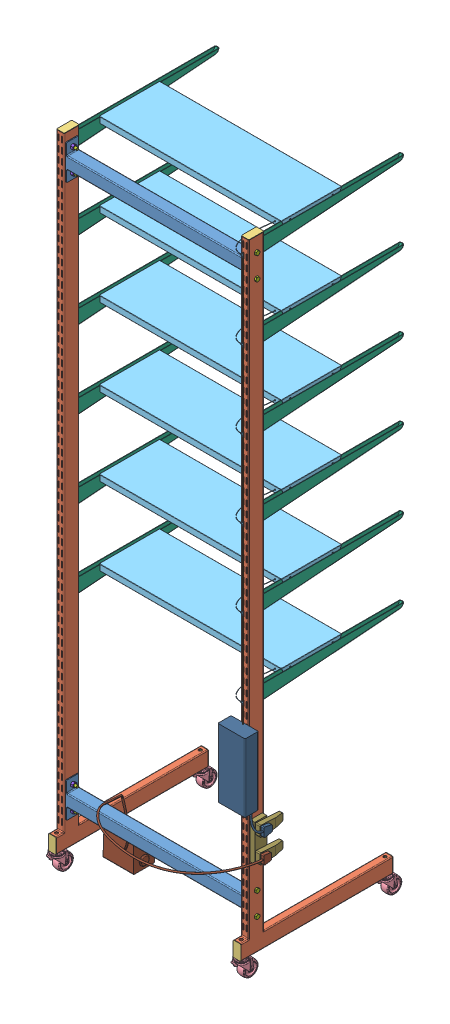
SolidWorks assembly elec system, configuration Default. Lengths in mm.
Overall size (697.81 2115 564.83).
53 component instances, 13 part files, 139 mates.
Components (placement in the parent):
- TB-600-1: TB-600 [Default] at (0 2029.5 0) size (585 115 40)
- TB-600-2: TB-600 [Default] at (0 205.5 0) size (585 115 40)
- TSU-F-L-P-1: TSU-F-L-P [Default] at (305 113.5 -25) size (25 2050 500)
- TSU-F-L-P-2: TSU-F-L-P [Default] at (-305 113.5 -25) size (25 2050 500)
- TSU-CAP-1: TSU-CAP [Default] at (-305.1 113.6 -39.9) x (-1 0 0) z (0 0 -1) size (25.2 50.2 6.5)
- TSU-CAP-2: TSU-CAP [Default] at (304.9 113.6 -39.9) x (-1 0 0) z (0 0 -1) size (25.2 50.2 6.5)
- TSU-CAP-3: TSU-CAP [Default] at (305.1 1703.4 -25.1) x (1 0 0) z (0 1 0) size (25.2 50.2 6.5)
- TSU-CAP-4: TSU-CAP [Default] at (304.9 113.6 -360.1) size (25.2 50.2 6.5)
- TSU-CAP-5: TSU-CAP [Default] at (-304.9 1703.4 -25.1) x (1 0 0) z (0 1 0) size (25.2 50.2 6.5)
- TSU-CAP-6: TSU-CAP [Default] at (-304.9 113.6 -360.1) size (25.2 50.2 6.5)
- 2834T320_THREADED-STEM SWIVEL CASTER-1: 2834T320_THREADED-STEM SWIVEL CASTER [2834T32] at (305 82.55 -437.5) x (0 0 -1) z (1 0 0) size (67.73 101.87 56.07)
- 2834T320_THREADED-STEM SWIVEL CASTER-2: 2834T320_THREADED-STEM SWIVEL CASTER [2834T32] at (-305 82.55 37.5) x (0 0 -1) z (1 0 0) size (67.73 101.87 56.07)
- 2834T320_THREADED-STEM SWIVEL CASTER-3: 2834T320_THREADED-STEM SWIVEL CASTER [2834T32] at (305 82.55 37.5) x (0 0 -1) z (1 0 0) size (67.73 101.87 56.07)
- 2834T320_THREADED-STEM SWIVEL CASTER-4: 2834T320_THREADED-STEM SWIVEL CASTER [2834T32] at (-305 82.55 -437.5) x (0 0 -1) z (1 0 0) size (67.73 101.87 56.07)
- TSS-600-1: TSS-600 [Default] at (0 818 -198.7822) size (607 37.13 331.17)
- TSUB-1: TSUB [Default] at (305 766.5 -25) x (-1 0 0) z (0 0 -1) size (14.07 50.86 484.03)
- TSUB-2: TSUB [Default] at (-305 766.5 -25) x (-1 0 0) z (0 0 -1) size (14.07 50.86 484.03)
- TSUB-3: TSUB [Default] at (-305 1022.5 -25) x (-1 0 0) z (0 0 -1) size (14.07 50.86 484.03)
- TSUB-4: TSUB [Default] at (305 1022.5 -25) x (-1 0 0) z (0 0 -1) size (14.07 50.86 484.03)
- TSS-600-2: TSS-600 [Default] at (0 1074 -198.7822) size (607 37.13 331.17)
- TSUB-5: TSUB [Default] at (-305 1534.5 -25) x (-1 0 0) z (0 0 -1) size (14.07 50.86 484.03)
- TSUB-6: TSUB [Default] at (305 1534.5 -25) x (-1 0 0) z (0 0 -1) size (14.07 50.86 484.03)
- TSS-600-3: TSS-600 [Default] at (0 1586 -198.7822) size (607 37.13 331.17)
- TSUB-7: TSUB [Default] at (-305 2046.5 -25) x (-1 0 0) z (0 0 -1) size (14.07 50.86 484.03)
- TSUB-8: TSUB [Default] at (305 2046.5 -25) x (-1 0 0) z (0 0 -1) size (14.07 50.86 484.03)
- TSS-600-4: TSS-600 [Default] at (0 2098 -198.7822) size (607 37.13 331.17)
- TSUB-9: TSUB [Default] at (-305 1278.5 -25) x (-1 0 0) z (0 0 -1) size (14.07 50.86 484.03)
- TSUB-10: TSUB [Default] at (305 1278.5 -25) x (-1 0 0) z (0 0 -1) size (14.07 50.86 484.03)
- TSS-600-5: TSS-600 [Default] at (0 1330 -198.7822) size (607 37.13 331.17)
- TSUB-11: TSUB [Default] at (-305 1790.5 -25) x (-1 0 0) z (0 0 -1) size (14.07 50.86 484.03)
- TSUB-12: TSUB [Default] at (305 1790.5 -25) x (-1 0 0) z (0 0 -1) size (14.07 50.86 484.03)
- TSS-600-6: TSS-600 [Default] at (0 1842 -198.7822) size (607 37.13 331.17)
- hex bolt gradeab2_bsi-10: hex bolt gradeab2_bsi [BS EN 28765 - M8x1 x 45 x 22-N] at (322.8 2067 0) x (-1 0 0) z (0 -0.924225 -0.381849) size (50.3 15.01 13)
- hex bolt gradeab2_bsi-11: hex bolt gradeab2_bsi [BS EN 28765 - M8x1 x 45 x 22-N] at (322.8 1992 0) x (-1 0 0) z (0 -0.999974 0.007224) size (50.3 15.01 13)
- hex bolt gradeab2_bsi-12: hex bolt gradeab2_bsi [BS EN 28765 - M8x1 x 45 x 22-N] at (-322.8 2067 0) size (50.3 15.01 13)
- hex bolt gradeab2_bsi-13: hex bolt gradeab2_bsi [BS EN 28765 - M8x1 x 45 x 22-N] at (-322.8 1992 0) size (50.3 15.01 13)
- hex bolt gradeab2_bsi-14: hex bolt gradeab2_bsi [BS EN 28765 - M8x1 x 45 x 22-N] at (-322.8 168 0) size (50.3 15.01 13)
- hex bolt gradeab2_bsi-15: hex bolt gradeab2_bsi [BS EN 28765 - M8x1 x 45 x 22-N] at (-322.8 243 0) size (50.3 15.01 13)
- hex bolt gradeab2_bsi-16: hex bolt gradeab2_bsi [BS EN 28765 - M8x1 x 45 x 22-N] at (322.8 168 0) x (-1 0 0) z (0 0.924225 0.381849) size (50.3 15.01 13)
- hex bolt gradeab2_bsi-17: hex bolt gradeab2_bsi [BS EN 28765 - M8x1 x 45 x 22-N] at (322.8 243 0) x (-1 0 0) z (0 -0.924225 -0.381849) size (50.3 15.01 13)
- hex nut gradec_bsi-1: hex nut gradec_bsi [BS EN 24034 - M8 - N] at (281.6 2067 0) x (0 0 1) z (-1 0 0) size (13 15.01 7.9)
- hex nut gradec_bsi-2: hex nut gradec_bsi [BS EN 24034 - M8 - N] at (281.6 1992 0) x (0 0 1) z (-1 0 0) size (13 15.01 7.9)
- hex nut gradec_bsi-3: hex nut gradec_bsi [BS EN 24034 - M8 - N] at (-281.6 2067 0) x (0 0 -1) z (1 0 0) size (13 15.01 7.9)
- hex nut gradec_bsi-4: hex nut gradec_bsi [BS EN 24034 - M8 - N] at (-281.6 1992 0) x (0 0.383049 0.923728) z (1 0 0) size (13 15.01 7.9)
- hex nut gradec_bsi-5: hex nut gradec_bsi [BS EN 24034 - M8 - N] at (-281.6 243 0) x (0 0 -1) z (1 0 0) size (13 15.01 7.9)
- hex nut gradec_bsi-6: hex nut gradec_bsi [BS EN 24034 - M8 - N] at (281.6 243 0) x (0 0 1) z (-1 0 0) size (13 15.01 7.9)
- hex nut gradec_bsi-7: hex nut gradec_bsi [BS EN 24034 - M8 - N] at (281.6 168 0) x (0 0 1) z (-1 0 0) size (13 15.01 7.9)
- hex nut gradec_bsi-8: hex nut gradec_bsi [BS EN 24034 - M8 - N] at (-281.6 168 0) x (0 0 -1) z (1 0 0) size (13 15.01 7.9)
- Part4-1: Part4 [Default] at origin
- Part1-1: Part1 [Default] at (0 2060.8692 -198.7822) x (-1 0 0) z (0 -1 0) size (2 2 1357)
- Part2-1: Part2 [Default] at (305 113.5 -25) x (0 0 -1) z (1 0 0) size (82.56 307.09 97.63)
- ele-1: ele [Default] at (0 5 -225) x (1 0 0) z (0 1 0) size (624.24 196.22 364.08)
- power brick-1: power brick [Default] at (317.5 113.5 -25) x (0 0 -1) z (1 0 0) size (82.62 120 30)
Mates (geometry in assembly coordinates):
- Coincident5: coincident aligned: plane of TB-600-2 through (0 205.5 0) normal (1 0 0)
- Coincident6: coincident aligned: plane of TB-600-2 through (0 205.5 0) normal (0 0 1)
- Tangent1: tangent anti-aligned: torus of 2834T320_THREADED-STEM SWIVEL CASTER-1
- Concentric5: concentric anti-aligned: cylinder of TSU-F-L-P-1 through (305 113.5 -437.5) axis (0 -1 0) radius 5.1; cylinder of 2834T320_THREADED-STEM SWIVEL CASTER-1 through (305 101.6 -437.5) axis (0 1 0) radius 4.7625
- Coincident7: coincident anti-aligned: plane of TB-600-2 through (292.5 205.5 0) normal (1 0 0); plane of TSU-F-L-P-1 through (292.5 2113.5 -22) normal (-1 0 0)
- Concentric6: concentric anti-aligned: cylinder of TB-600-2 through (292.5 243 0) axis (-1 0 0) radius 4.5; cylinder of TSU-F-L-P-1 through (290.9 243 0) axis (1 0 0) radius 4.5
- Coincident8: coincident anti-aligned: plane of TSU-F-L-P-1 through (305 63.5 -450) normal (0 -1 0); plane of 2834T320_THREADED-STEM SWIVEL CASTER-1 through (305 63.5 -421.3957) normal (0 1 0)
- Concentric7: concentric anti-aligned: cylinder of TB-600-1 through (292.5 2067 0) axis (-1 0 0) radius 4.5; cylinder of TSU-F-L-P-1 through (292.5 2067 0) axis (1 0 0) radius 4.5
- Coincident9: coincident anti-aligned: plane of TB-600-1 through (292.5 2029.5 0) normal (1 0 0); plane of TSU-F-L-P-1 through (292.5 2113.5 -22) normal (-1 0 0)
- Concentric8: concentric aligned: cylinder of TB-600-2 through (-292.5 168 0) axis (1 0 0) radius 4.5; cylinder of TSU-F-L-P-2 through (-319.1 168 0) axis (1 0 0) radius 4.5
- Coincident10: coincident anti-aligned: plane of TB-600-2 through (-292.5 205.5 0) normal (-1 0 0); plane of TSU-F-L-P-2 through (-292.5 2113.5 -22) normal (1 0 0)
- Concentric9: concentric anti-aligned: cylinder of TSU-F-L-P-2 through (-305 113.5 -437.5) axis (0 -1 0) radius 5.1; cylinder of 2834T320_THREADED-STEM SWIVEL CASTER-4 through (-305 101.6 -437.5) axis (0 1 0) radius 4.7625
- Concentric10: concentric aligned: cylinder of TB-600-1 through (-292.5 1992 0) axis (1 0 0) radius 4.5; cylinder of TSU-F-L-P-2 through (-317.5 1992 0) axis (1 0 0) radius 4.5
- Concentric11: concentric aligned: cylinder of TB-600-1 through (-292.5 2067 0) axis (1 0 0) radius 4.5; cylinder of TSU-F-L-P-2 through (-317.5 2067 0) axis (1 0 0) radius 4.5
- Parallel4: parallel aligned: plane of TSU-F-L-P-1 through (317.5 2113.5 -22) normal (1 0 0); plane of 2834T320_THREADED-STEM SWIVEL CASTER-1 through (316.9062 47.2916 -458.1375) normal (1 0 0)
- Coincident16: coincident anti-aligned: plane of TSU-F-L-P-2 through (-305 63.5 -450) normal (0 -1 0); plane of 2834T320_THREADED-STEM SWIVEL CASTER-4 through (-305 63.5 -421.3957) normal (0 1 0)
- Concentric12: concentric anti-aligned: cylinder of TSU-F-L-P-1 through (305 113.5 37.5) axis (0 -1 0) radius 5.1; cylinder of 2834T320_THREADED-STEM SWIVEL CASTER-3 through (305 101.6 37.5) axis (0 1 0) radius 4.7625
- Coincident17: coincident anti-aligned: plane of TSU-F-L-P-1 through (305 63.5 -450) normal (0 -1 0); plane of 2834T320_THREADED-STEM SWIVEL CASTER-3 through (305 63.5 53.6043) normal (0 1 0)
- Coincident18: coincident aligned: plane of 2834T320_THREADED-STEM SWIVEL CASTER-1 through (316.9062 47.2916 -458.1375) normal (1 0 0); plane of 2834T320_THREADED-STEM SWIVEL CASTER-3 through (316.9062 47.2916 16.8625) normal (1 0 0)
- Concentric13: concentric anti-aligned: cylinder of TSU-F-L-P-2 through (-305 113.5 37.5) axis (0 -1 0) radius 5.1; cylinder of 2834T320_THREADED-STEM SWIVEL CASTER-2 through (-305 101.6 37.5) axis (0 1 0) radius 4.7625
- Coincident19: coincident anti-aligned: plane of TSU-F-L-P-2 through (-305 63.5 -450) normal (0 -1 0); plane of 2834T320_THREADED-STEM SWIVEL CASTER-2 through (-305 63.5 53.6043) normal (0 1 0)
- Parallel6: parallel aligned: plane of TSU-F-L-P-2 through (-317.5 2113.5 -22) normal (-1 0 0); plane of 2834T320_THREADED-STEM SWIVEL CASTER-2 through (-316.9062 47.2916 16.8625) normal (-1 0 0)
- Coincident21: coincident anti-aligned: plane of TSU-F-L-P-1 through (294 2113.5 0) normal (1 0 0); plane of TSU-CAP-4 through (294 113.6 45) normal (-1 0 0)
- Coincident22: coincident anti-aligned: plane of TSU-F-L-P-1 through (314.5 112 -450) normal (0 -1 0); plane of TSU-CAP-4 through (304.9 112 45) normal (0 1 0)
- Coincident23: coincident anti-aligned: plane of TSU-F-L-P-1 through (314.5 110.5 50) normal (0 0 1); plane of TSU-CAP-4 through (304.9 113.6 50) normal (0 0 -1)
- Coincident24: coincident anti-aligned: plane of TSU-F-L-P-2 through (-294 2113.5 0) normal (-1 0 0); plane of TSU-CAP-6 through (-294 113.6 45) normal (1 0 0)
- Coincident25: coincident anti-aligned: plane of TSU-F-L-P-2 through (-295.5 112 -450) normal (0 -1 0); plane of TSU-CAP-6 through (-304.9 112 45) normal (0 1 0)
- Coincident26: coincident anti-aligned: plane of TSU-F-L-P-2 through (-295.5 110.5 50) normal (0 0 1); plane of TSU-CAP-6 through (-304.9 113.6 50) normal (0 0 -1)
- Coincident27: coincident anti-aligned: plane of TSU-F-L-P-1 through (294 2113.5 0) normal (1 0 0); plane of TSU-CAP-2 through (294 113.6 -445) normal (-1 0 0)
- Coincident28: coincident anti-aligned: plane of TSU-F-L-P-1 through (314.5 112 -450) normal (0 -1 0); plane of TSU-CAP-2 through (304.9 112 -445) normal (0 1 0)
- Coincident29: coincident anti-aligned: plane of TSU-F-L-P-1 through (314.5 110.5 -450) normal (0 0 -1); plane of TSU-CAP-2 through (304.9 113.6 -450) normal (0 0 1)
- Coincident30: coincident anti-aligned: plane of TSU-F-L-P-2 through (-316 2113.5 0) normal (1 0 0); plane of TSU-CAP-1 through (-316 113.6 -445) normal (-1 0 0)
- Coincident31: coincident anti-aligned: plane of TSU-F-L-P-2 through (-295.5 112 -450) normal (0 -1 0); plane of TSU-CAP-1 through (-305.1 112 -445) normal (0 1 0)
- Coincident32: coincident anti-aligned: plane of TSU-F-L-P-2 through (-295.5 110.5 -450) normal (0 0 -1); plane of TSU-CAP-1 through (-305.1 113.6 -450) normal (0 0 1)
- Coincident33: coincident anti-aligned: plane of TSU-F-L-P-1 through (316 2113.5 0) normal (-1 0 0); plane of TSU-CAP-3 through (316 2108.5 -25.1) normal (1 0 0)
- Coincident34: coincident anti-aligned: plane of TSU-F-L-P-1 through (314.5 2113.5 -23.5) normal (0 0 1); plane of TSU-CAP-3 through (305.1 2108.5 -23.5) normal (0 0 -1)
- Coincident35: coincident anti-aligned: plane of TSU-F-L-P-1 through (314.5 2113.5 -22) normal (0 1 0); plane of TSU-CAP-3 through (305.1 2113.5 -25.1) normal (0 -1 0)
- Coincident36: coincident anti-aligned: plane of TSU-F-L-P-2 through (-294 2113.5 0) normal (-1 0 0); plane of TSU-CAP-5 through (-294 2108.5 -25.1) normal (1 0 0)
- Coincident37: coincident anti-aligned: plane of TSU-F-L-P-2 through (-295.5 2113.5 -23.5) normal (0 0 1); plane of TSU-CAP-5 through (-304.9 2108.5 -23.5) normal (0 0 -1)
- Coincident38: coincident anti-aligned: plane of TSU-F-L-P-2 through (-295.5 2113.5 -22) normal (0 1 0); plane of TSU-CAP-5 through (-304.9 2113.5 -25.1) normal (0 -1 0)
- Parallel7: parallel aligned: plane of TSU-F-L-P-2 through (-292.5 2113.5 -22) normal (1 0 0); plane of 2834T320_THREADED-STEM SWIVEL CASTER-4 through (-293.0938 47.2916 -458.1375) normal (1 0 0)
- Coincident41: coincident anti-aligned: plane of TSU-F-L-P-1 through (298 273.5 0.001) normal (1 0 0); plane of TSUB-1 through (298 766.5 -25) normal (-1 0 0)
- Coincident42: coincident anti-aligned: plane of TSU-F-L-P-1 through (305 2113.5 -25) normal (0 0 -1); plane of TSUB-1 through (312 766.5 -25) normal (0 0 1)
- Parallel8: parallel: line of TSU-F-L-P-1 through (309 342 -23.5) axis (0 0 -1); plane of TSUB-1 through (298 816.5 -25) normal (0 1 0)
- Coincident44: coincident anti-aligned: plane of TSS-600-1 through (299.5 798 -198.7822) normal (-1 0 0); plane of TSUB-1 through (299.5 766.5 -25) normal (1 0 0)
- Coincident45: coincident anti-aligned: plane of TSS-600-1 through (301 816.5 -100.2822) normal (0 -1 0); plane of TSUB-1 through (298 816.5 -25) normal (0 1 0)
- Coincident46: coincident anti-aligned: plane of TSU-F-L-P-2 through (-312 369.5 0.001) normal (1 0 0); plane of TSUB-2 through (-312 766.5 -25) normal (-1 0 0)
- Coincident47: coincident anti-aligned: plane of TSU-F-L-P-2 through (-305 2113.5 -25) normal (0 0 -1); plane of TSUB-2 through (-312 766.5 -25) normal (0 0 1)
- Coincident48: coincident anti-aligned: plane of TSS-600-1 through (301 816.5 -100.2822) normal (0 -1 0); plane of TSUB-2 through (-312 816.5 -25) normal (0 1 0)
- Coincident49: coincident anti-aligned: plane of TSU-F-L-P-1 through (312 1041.5 0.001) normal (-1 0 0); plane of TSUB-4 through (312 1022.5 -25) normal (1 0 0)
- Coincident50: coincident anti-aligned: plane of TSU-F-L-P-1 through (305 2113.5 -25) normal (0 0 -1); plane of TSUB-4 through (312 1022.5 -25) normal (0 0 1)
- Coincident51: coincident anti-aligned: plane of TSU-F-L-P-2 through (-298 1073.5 0.001) normal (-1 0 0); plane of TSUB-3 through (-298 1022.5 -25) normal (1 0 0)
- Coincident52: coincident anti-aligned: plane of TSU-F-L-P-2 through (-305 2113.5 -25) normal (0 0 -1); plane of TSUB-3 through (-312 1022.5 -25) normal (0 0 1)
- Coincident53: coincident anti-aligned: plane of TSUB-4 through (298 1072.5 -25) normal (0 1 0); plane of TSS-600-2 through (301 1072.5 -100.2822) normal (0 -1 0)
- Coincident54: coincident anti-aligned: plane of TSUB-3 through (-312 1072.5 -25) normal (0 1 0); plane of TSS-600-2 through (301 1072.5 -100.2822) normal (0 -1 0)
- Coincident55: coincident anti-aligned: plane of TSUB-4 through (299.5 1022.5 -25) normal (1 0 0); plane of TSS-600-2 through (299.5 1054 -198.7822) normal (-1 0 0)
- Coincident56: coincident anti-aligned: plane of TSUB-6 through (299.5 1534.5 -25) normal (1 0 0); plane of TSS-600-3 through (299.5 1566 -198.7822) normal (-1 0 0)
- Coincident57: coincident anti-aligned: plane of TSUB-6 through (298 1584.5 -25) normal (0 1 0); plane of TSS-600-3 through (301 1584.5 -100.2822) normal (0 -1 0)
- Coincident58: coincident anti-aligned: plane of TSUB-5 through (-312 1584.5 -25) normal (0 1 0); plane of TSS-600-3 through (301 1584.5 -100.2822) normal (0 -1 0)
- Coincident59: coincident anti-aligned: plane of TSUB-8 through (299.5 2046.5 -25) normal (1 0 0); plane of TSS-600-4 through (299.5 2078 -198.7822) normal (-1 0 0)
- Coincident60: coincident anti-aligned: plane of TSUB-8 through (298 2096.5 -25) normal (0 1 0); plane of TSS-600-4 through (301 2096.5 -100.2822) normal (0 -1 0)
- Coincident61: coincident anti-aligned: plane of TSUB-7 through (-312 2096.5 -25) normal (0 1 0); plane of TSS-600-4 through (301 2096.5 -100.2822) normal (0 -1 0)
- Coincident62: coincident anti-aligned: plane of TSUB-10 through (299.5 1278.5 -25) normal (1 0 0); plane of TSS-600-5 through (299.5 1310 -198.7822) normal (-1 0 0)
- Coincident63: coincident anti-aligned: plane of TSUB-10 through (298 1328.5 -25) normal (0 1 0); plane of TSS-600-5 through (301 1328.5 -100.2822) normal (0 -1 0)
- Coincident64: coincident anti-aligned: plane of TSUB-9 through (-312 1328.5 -25) normal (0 1 0); plane of TSS-600-5 through (301 1328.5 -100.2822) normal (0 -1 0)
- Coincident65: coincident anti-aligned: plane of TSUB-12 through (299.5 1790.5 -25) normal (1 0 0); plane of TSS-600-6 through (299.5 1822 -198.7822) normal (-1 0 0)
- Coincident66: coincident anti-aligned: plane of TSUB-12 through (298 1840.5 -25) normal (0 1 0); plane of TSS-600-6 through (301 1840.5 -100.2822) normal (0 -1 0)
- Coincident67: coincident anti-aligned: plane of TSUB-11 through (-312 1840.5 -25) normal (0 1 0); plane of TSS-600-6 through (301 1840.5 -100.2822) normal (0 -1 0)
- Coincident70: coincident anti-aligned: plane of TSU-F-L-P-1 through (305 2113.5 -25) normal (0 0 -1); plane of TSUB-10 through (298 1278.5 -25) normal (0 0 1)
- Coincident71: coincident anti-aligned: plane of TSU-F-L-P-2 through (-305 2113.5 -25) normal (0 0 -1); plane of TSUB-9 through (-312 1278.5 -25) normal (0 0 1)
- Coincident72: coincident aligned: plane of TSUB-3 through (-298 1022.5 -25) normal (1 0 0); plane of TSUB-9 through (-298 1278.5 -25) normal (1 0 0)
- Coincident73: coincident aligned: plane of TSUB-4 through (298 1022.5 -25) normal (-1 0 0); plane of TSUB-10 through (298 1278.5 -25) normal (-1 0 0)
- Coincident74: coincident anti-aligned: plane of TSU-F-L-P-1 through (305 2113.5 -25) normal (0 0 -1); plane of TSUB-6 through (298 1534.5 -25) normal (0 0 1)
- Coincident75: coincident anti-aligned: plane of TSU-F-L-P-2 through (-305 2113.5 -25) normal (0 0 -1); plane of TSUB-5 through (-312 1534.5 -25) normal (0 0 1)
- Coincident76: coincident aligned: plane of TSUB-5 through (-298 1534.5 -25) normal (1 0 0); plane of TSUB-9 through (-298 1278.5 -25) normal (1 0 0)
- Coincident78: coincident aligned: plane of TSUB-6 through (312 1534.5 -25) normal (1 0 0); plane of TSUB-12 through (312 1790.5 -25) normal (1 0 0)
- Coincident79: coincident aligned: plane of TSUB-6 through (298 1534.5 -25) normal (-1 0 0); plane of TSUB-10 through (298 1278.5 -25) normal (-1 0 0)
- Coincident80: coincident anti-aligned: plane of TSU-F-L-P-1 through (305 2113.5 -25) normal (0 0 -1); plane of TSUB-12 through (298 1790.5 -25) normal (0 0 1)
- Coincident81: coincident anti-aligned: plane of TSU-F-L-P-2 through (-312 1873.5 0.001) normal (1 0 0); plane of TSUB-11 through (-312 1790.5 -25) normal (-1 0 0)
- Coincident82: coincident anti-aligned: plane of TSU-F-L-P-2 through (-305 2113.5 -25) normal (0 0 -1); plane of TSUB-11 through (-312 1790.5 -25) normal (0 0 1)
- Coincident83: coincident anti-aligned: plane of TSU-F-L-P-2 through (-312 1969.5 0.001) normal (1 0 0); plane of TSUB-7 through (-312 2046.5 -25) normal (-1 0 0)
- Coincident84: coincident anti-aligned: plane of TSU-F-L-P-2 through (-305 2113.5 -25) normal (0 0 -1); plane of TSUB-7 through (-312 2046.5 -25) normal (0 0 1)
- Coincident85: coincident anti-aligned: plane of TSU-F-L-P-1 through (298 2001.5 0.001) normal (1 0 0); plane of TSUB-8 through (298 2046.5 -25) normal (-1 0 0)
- Coincident86: coincident anti-aligned: plane of TSU-F-L-P-1 through (305 2113.5 -25) normal (0 0 -1); plane of TSUB-8 through (298 2046.5 -25) normal (0 0 1)
- Coincident89: coincident: line of TSU-F-L-P-1 through (309 2070 -23.5) axis (0 0 -1); plane of TSUB-8 through (333.2603 2070 -25) normal (0 1 0)
- Coincident90: coincident aligned: plane of TSS-600-4 through (301 2098 -298.7822) normal (0 0 -1); plane of TSS-600-6 through (301 1842 -298.7822) normal (0 0 -1)
- Coincident91: coincident aligned: plane of TSS-600-3 through (301 1586 -298.7822) normal (0 0 -1); plane of TSS-600-6 through (301 1842 -298.7822) normal (0 0 -1)
- Coincident93: coincident aligned: plane of TSS-600-3 through (301 1586 -298.7822) normal (0 0 -1); plane of TSS-600-5 through (301 1330 -298.7822) normal (0 0 -1)
- Coincident94: coincident aligned: plane of TSS-600-2 through (301 1074 -298.7822) normal (0 0 -1); plane of TSS-600-5 through (301 1330 -298.7822) normal (0 0 -1)
- Coincident95: coincident aligned: plane of TSS-600-1 through (301 818 -298.7822) normal (0 0 -1); plane of TSS-600-2 through (301 1074 -298.7822) normal (0 0 -1)
- Coincident153: coincident: line of TSU-F-L-P-1 through (312 1814 -23.5) axis (0 0 -1); plane of TSUB-12 through (333.2603 1814 -25) normal (0 1 0)
- Coincident155: coincident: line of TSU-F-L-P-1 through (312 1558 -23.5) axis (0 0 -1); plane of TSUB-6 through (333.2603 1558 -25) normal (0 1 0)
- Coincident157: coincident: line of TSU-F-L-P-1 through (312 1302 -23.5) axis (0 0 -1); plane of TSUB-10 through (333.2603 1302 -25) normal (0 1 0)
- Coincident159: coincident: line of TSU-F-L-P-1 through (312 1046 -23.5) axis (0 0 -1); plane of TSUB-4 through (333.2603 1046 -25) normal (0 1 0)
- Coincident167: coincident: line of TSU-F-L-P-1 through (312 790 -23.5) axis (0 0 -1); plane of TSUB-1 through (333.2603 790 -25) normal (0 1 0)
- Concentric15: concentric aligned: cylinder of TSU-F-L-P-1 through (292.5 2067 0) axis (1 0 0) radius 4.5; cylinder of hex bolt gradeab2_bsi-10 through (322.8 2067 0) axis (1 0 0) radius 4
- Coincident181: coincident anti-aligned: plane of TSU-F-L-P-1 through (317.5 2113.5 -22) normal (1 0 0); plane of hex bolt gradeab2_bsi-10 through (317.5 2069.866 -6.9368) normal (-1 0 0)
- Concentric16: concentric aligned: cylinder of TSU-F-L-P-1 through (292.5 1992 0) axis (1 0 0) radius 4.5; cylinder of hex bolt gradeab2_bsi-11 through (322.8 1992 0) axis (1 0 0) radius 4
- Coincident182: coincident anti-aligned: plane of TSU-F-L-P-1 through (317.5 2113.5 -22) normal (1 0 0); plane of hex bolt gradeab2_bsi-11 through (317.5 1991.9458 -7.5054) normal (-1 0 0)
- Concentric17: concentric anti-aligned: cylinder of TB-600-1 through (-292.5 2067 0) axis (1 0 0) radius 4.5; cylinder of hex bolt gradeab2_bsi-12 through (-322.8 2067 0) axis (-1 0 0) radius 4
- Coincident183: coincident anti-aligned: plane of TSU-F-L-P-2 through (-317.5 2113.5 -22) normal (-1 0 0); plane of hex bolt gradeab2_bsi-12 through (-317.5 2074.5056 0) normal (1 0 0)
- Concentric18: concentric anti-aligned: cylinder of TB-600-1 through (-292.5 1992 0) axis (1 0 0) radius 4.5; cylinder of hex bolt gradeab2_bsi-13 through (-322.8 1992 0) axis (-1 0 0) radius 4
- Coincident184: coincident anti-aligned: plane of TSU-F-L-P-2 through (-317.5 2113.5 -22) normal (-1 0 0); plane of hex bolt gradeab2_bsi-13 through (-317.5 1999.5056 0) normal (1 0 0)
- Concentric19: concentric anti-aligned: cylinder of TB-600-2 through (-292.5 243 0) axis (1 0 0) radius 4.5; cylinder of hex bolt gradeab2_bsi-15 through (-322.8 243 0) axis (-1 0 0) radius 4
- Coincident185: coincident anti-aligned: plane of TSU-F-L-P-2 through (-317.5 2113.5 -22) normal (-1 0 0); plane of hex bolt gradeab2_bsi-15 through (-317.5 250.5056 0) normal (1 0 0)
- Concentric20: concentric anti-aligned: cylinder of TB-600-2 through (-292.5 168 0) axis (1 0 0) radius 4.5; cylinder of hex bolt gradeab2_bsi-14 through (-322.8 168 0) axis (-1 0 0) radius 4
- Coincident186: coincident anti-aligned: plane of TSU-F-L-P-2 through (-317.5 2113.5 -22) normal (-1 0 0); plane of hex bolt gradeab2_bsi-14 through (-317.5 175.5056 0) normal (1 0 0)
- Concentric21: concentric anti-aligned: cylinder of TB-600-2 through (292.5 243 0) axis (-1 0 0) radius 4.5; cylinder of hex bolt gradeab2_bsi-17 through (322.8 243 0) axis (1 0 0) radius 4
- Coincident187: coincident anti-aligned: plane of TSU-F-L-P-1 through (317.5 2113.5 -22) normal (1 0 0); plane of hex bolt gradeab2_bsi-17 through (317.5 245.866 -6.9368) normal (-1 0 0)
- Concentric22: concentric aligned: cylinder of TSU-F-L-P-1 through (290.9 168 0) axis (1 0 0) radius 4.5; cylinder of hex bolt gradeab2_bsi-16 through (322.8 168 0) axis (1 0 0) radius 4
- Coincident188: coincident anti-aligned: plane of TSU-F-L-P-1 through (317.5 2113.5 -22) normal (1 0 0); plane of hex bolt gradeab2_bsi-16 through (317.5 165.134 6.9368) normal (-1 0 0)
- Concentric23: concentric anti-aligned: cylinder of hex bolt gradeab2_bsi-10 through (322.8 2067 0) axis (1 0 0) radius 4; cylinder of hex nut gradec_bsi-1 through (289.5 2067 0) axis (-1 0 0) radius 3.4
- Coincident189: coincident anti-aligned: plane of TB-600-1 through (289.5 2029.5 0) normal (-1 0 0); plane of hex nut gradec_bsi-1 through (289.5 2074.5056 0) normal (1 0 0)
- Concentric24: concentric anti-aligned: cylinder of hex bolt gradeab2_bsi-11 through (322.8 1992 0) axis (1 0 0) radius 4; cylinder of hex nut gradec_bsi-2 through (289.5 1992 0) axis (-1 0 0) radius 3.4
- Coincident190: coincident anti-aligned: plane of TB-600-1 through (289.5 2029.5 0) normal (-1 0 0); plane of hex nut gradec_bsi-2 through (289.5 1999.5056 0) normal (1 0 0)
- Concentric25: concentric anti-aligned: cylinder of hex bolt gradeab2_bsi-12 through (-322.8 2067 0) axis (-1 0 0) radius 4; cylinder of hex nut gradec_bsi-3 through (-289.5 2067 0) axis (1 0 0) radius 3.4
- Coincident191: coincident anti-aligned: plane of TB-600-1 through (-289.5 2029.5 0) normal (1 0 0); plane of hex nut gradec_bsi-3 through (-289.5 2074.5056 0) normal (-1 0 0)
- Concentric26: concentric anti-aligned: cylinder of hex bolt gradeab2_bsi-13 through (-322.8 1992 0) axis (-1 0 0) radius 4; cylinder of hex nut gradec_bsi-4 through (-289.5 1992 0) axis (1 0 0) radius 3.4
- Coincident192: coincident anti-aligned: plane of TB-600-1 through (-289.5 2029.5 0) normal (1 0 0); plane of hex nut gradec_bsi-4 through (-289.5 1985.0669 2.875) normal (-1 0 0)
- Concentric27: concentric anti-aligned: cylinder of hex bolt gradeab2_bsi-15 through (-322.8 243 0) axis (-1 0 0) radius 4; cylinder of hex nut gradec_bsi-5 through (-289.5 243 0) axis (1 0 0) radius 3.4
- Coincident193: coincident anti-aligned: plane of TB-600-2 through (-289.5 205.5 0) normal (1 0 0); plane of hex nut gradec_bsi-5 through (-289.5 250.5056 0) normal (-1 0 0)
- Concentric28: concentric anti-aligned: cylinder of hex bolt gradeab2_bsi-14 through (-322.8 168 0) axis (-1 0 0) radius 4; cylinder of hex nut gradec_bsi-8 through (-289.5 168 0) axis (1 0 0) radius 3.4
- Coincident194: coincident anti-aligned: plane of TB-600-2 through (-289.5 205.5 0) normal (1 0 0); plane of hex nut gradec_bsi-8 through (-289.5 175.5056 0) normal (-1 0 0)
- Concentric29: concentric anti-aligned: cylinder of hex bolt gradeab2_bsi-17 through (322.8 243 0) axis (1 0 0) radius 4; cylinder of hex nut gradec_bsi-6 through (289.5 243 0) axis (-1 0 0) radius 3.4
- Concentric30: concentric anti-aligned: cylinder of hex bolt gradeab2_bsi-16 through (322.8 168 0) axis (1 0 0) radius 4; cylinder of hex nut gradec_bsi-7 through (289.5 168 0) axis (-1 0 0) radius 3.4
- Coincident195: coincident anti-aligned: plane of TB-600-2 through (289.5 205.5 0) normal (-1 0 0); plane of hex nut gradec_bsi-6 through (289.5 250.5056 0) normal (1 0 0)
- Coincident196: coincident anti-aligned: plane of TB-600-2 through (289.5 205.5 0) normal (-1 0 0); plane of hex nut gradec_bsi-7 through (289.5 175.5056 0) normal (1 0 0)
- InPlace2: in place: plane of TSS-600-4 through (0 2060.8692 30.3916) normal (0 -1 0); plane of ? through (0 2060.8692 0) normal (0 -1 0); moOrthogonalPlaneRef_w of TSS-600-4 through (0 2060.8692 30.3916) normal (0 -1 0); plane of ? through (0 2060.8692 0) normal (0 0 -1); plane of TSS-600-4 through (0 2060.8692 30.3916) normal (0 -1 0); plane of ? through (0 2060.8692 0) normal (-1 0 0); plane of TSS-600-4 through (0 2060.8692 30.3916) normal (0 -1 0); unknown of Part1-1
- Coincident251: coincident aligned: plane of TSS-600-4; plane of Part1-1
- Coincident252: coincident aligned: moOrthogonalPlaneRef_w of TSS-600-4 through (0 2060.8692 -198.7822) normal (0 0 -1); plane of Part1-1 through (0 2060.8692 -198.7822) normal (0 0 -1)
- Coincident253: coincident anti-aligned: moOrthogonalPlaneRef_w of TSS-600-4 through (0 2060.8692 -198.7822) normal (1 0 0); plane of Part1-1 through (0 2060.8692 -198.7822) normal (-1 0 0)
- InPlace3: in place: plane of TSU-F-L-P-1 through (305 113.5 -25) normal (1 0 0); plane of Part2-1 through (305 113.5 -25) normal (1 0 0); plane of TSU-F-L-P-1 through (305 113.5 -25) normal (1 0 0); plane of Part2-1 through (305 113.5 -25) normal (0 1 0); plane of TSU-F-L-P-1 through (305 113.5 -25) normal (1 0 0); plane of Part2-1 through (305 113.5 -25) normal (0 0 -1); plane of TSU-F-L-P-1 through (305 113.5 -25) normal (1 0 0); unknown of Part2-1
- Coincident254: coincident aligned: plane of TSU-F-L-P-1; plane of Part2-1
- Coincident255: coincident aligned: moOrthogonalPlaneRef_w of TSU-F-L-P-1; plane of Part2^Assem1-1 through (305 113.5 -25) normal (0 1 0)
- Coincident256: coincident anti-aligned: moOrthogonalPlaneRef_w of TSU-F-L-P-1 through (-25 0 0) axis (1 0 0); plane of Part2^Assem1-1 through (305 113.5 -25) normal (0 0 -1)
- InPlace5: in place: plane of TSU-F-L-P-1 through (317.5 2113.5 -22) normal (1 0 0); plane of ? through (317.5 0 0) normal (1 0 0); plane of TSU-F-L-P-1 through (317.5 2113.5 -22) normal (1 0 0); plane of ? through (317.5 0 0) normal (0 1 0); plane of TSU-F-L-P-1 through (317.5 2113.5 -22) normal (1 0 0); plane of ? through (317.5 0 0) normal (0 0 -1); plane of TSU-F-L-P-1 through (317.5 2113.5 -22) normal (1 0 0); unknown of power brick-1
- Coincident260: coincident aligned: plane of TSU-F-L-P-1; plane of power brick-1
- Coincident261: coincident aligned: moOrthogonalPlaneRef_w of TSU-F-L-P-1 through (317.5 113.5 -25) normal (0 1 0); plane of Part4^Assem1-1 through (317.5 113.5 -25) normal (0 1 0)
- Coincident262: coincident anti-aligned: moOrthogonalPlaneRef_w of TSU-F-L-P-1 through (317.5 113.5 -25) normal (0 0 1); plane of Part4^Assem1-1 through (317.5 113.5 -25) normal (0 0 -1)
